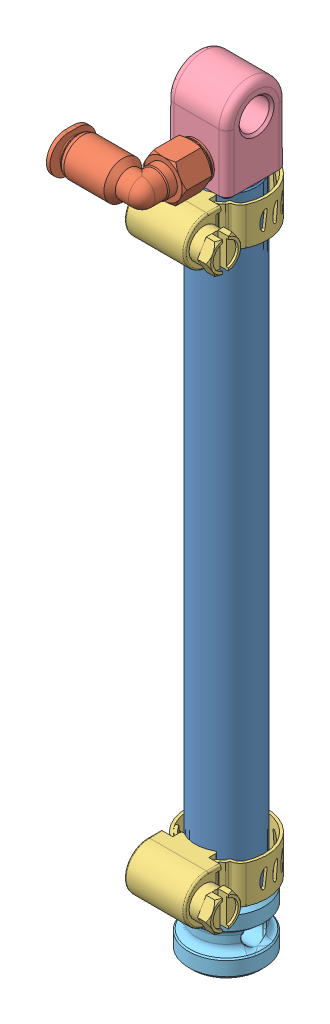
SolidWorks assembly AARL_QR_PN_PA_FL_SH_EX-Extensor, configuration Default. Lengths in mm.
Overall size (26.6 161.92 31.28).
6 component instances, 5 part files, 15 mates.
Components (placement in the parent):
- AARL_QR_PN_PA_FL_SH_EX_001-1: AARL_QR_PN_PA_FL_SH_EX_001 [Resting] at origin size (12.7 130.18 12.7)
- AARL_Puppy_18_02_57_010-QSML-M3-4-1: AARL_Puppy_18_02_57_010-QSML-M3-4 [Default] at (0 69.85 17.85) x (-1 0 0) z (0 0 -1) size (20.32 8 18.9)
- AARL_Puppy_18_02_57_011-5388K140_Hose-Clamp-1: AARL_Puppy_18_02_57_011-5388K140_Hose-Clamp [5388K14] at (0 -60.1345 0) x (1 0 0) z (0 -1 0) size (19.43 23.71 9.91)
- AARL_Puppy_18_02_57_011-5388K140_Hose-Clamp-2: AARL_Puppy_18_02_57_011-5388K140_Hose-Clamp [5388K14] at (0 60.1345 0) x (1 0 0) z (0 -1 0) size (19.43 23.71 9.91)
- AARL_QR_PN_EP_001-1: AARL_QR_PN_EP_001 [Default] at (0 77.7875 0) x (0 0 1) z (-1 0 0) size (12.7 31.75 12.7)
- AARL_QR_PN_EP_002-1: AARL_QR_PN_EP_002 [Default] at (0 -65.0875 0) x (-1 0 0) z (0 0 1) size (15.88 25.4 15.88)
Mates (geometry in assembly coordinates):
- Concentric1: concentric aligned: cylinder of AARL_QR_PN_PA_FL_SH_EX_001-1 through (0 11.6086 0) axis (0 1 0) radius 4.7625; cylinder of AARL_QR_PN_EP_001-1 through (0 87.3315 0) axis (0 1 0) radius 4.3656
- Parallel1: parallel aligned: plane of AARL_QR_PN_EP_001-1 through (-6.35 65.0875 6.35) normal (0 0 1)
- Coincident2: coincident anti-aligned: plane of AARL_QR_PN_PA_FL_SH_EX_001-1 through (4.7625 65.0875 0) normal (0 1 0); plane of AARL_QR_PN_EP_001-1 through (-6.35 65.0875 -6.35) normal (0 -1 0)
- Concentric2: concentric aligned: cylinder of AARL_Puppy_18_02_57_010-QSML-M3-4-1 through (0 69.85 6.35) axis (0 0 1) radius 1.5; cylinder of AARL_QR_PN_EP_001-1 through (0 69.85 6.35) axis (0 0 1) radius 2.0193
- Coincident3: coincident anti-aligned: plane of AARL_Puppy_18_02_57_010-QSML-M3-4-1 through (0 69.85 6.35) normal (0 0 -1); plane of AARL_QR_PN_EP_001-1 through (-6.35 65.0875 6.35) normal (0 0 1)
- Parallel2: parallel aligned: plane of AARL_Puppy_18_02_57_010-QSML-M3-4-1 through (2.3094 65.85 13.4056) normal (0 -1 0); plane of AARL_QR_PN_EP_001-1 through (-6.35 65.0875 -6.35) normal (0 -1 0)
- Concentric3: concentric anti-aligned: cylinder of AARL_QR_PN_PA_FL_SH_EX_001-1 through (0 11.6086 0) axis (0 1 0) radius 4.7625; cylinder of AARL_QR_PN_EP_002-1 through (0 -72.8252 0) axis (0 -1 0) radius 4.3656
- Coincident5: coincident anti-aligned: plane of AARL_QR_PN_PA_FL_SH_EX_001-1 through (6.35 -65.0875 0) normal (0 -1 0); plane of AARL_QR_PN_EP_002-1 through (-4.3656 -65.0875 0) normal (0 1 0)
- Parallel3: parallel anti-aligned: cylinder of AARL_QR_PN_EP_001-1 through (-6.35 77.7875 0) axis (1 0 0) radius 3.175; cylinder of AARL_QR_PN_EP_002-1 through (7.9375 -71.4375 0) axis (-1 0 0) radius 2.3813
- Concentric5: concentric aligned: cylinder of AARL_QR_PN_PA_FL_SH_EX_001-1 through (0 11.6086 0) axis (0 1 0) radius 6.35; cylinder of AARL_Puppy_18_02_57_011-5388K140_Hose-Clamp-2 through (0 56.1658 0) axis (0 1 0) radius 7.9375
- Coincident6: coincident aligned: plane of AARL_Puppy_18_02_57_011-5388K140_Hose-Clamp-2 through (6.35 60.1345 10.2337) normal (1 0 0); plane of AARL_QR_PN_EP_001-1 through (6.35 77.7875 0) normal (1 0 0)
- Coincident7: coincident anti-aligned: plane of AARL_Puppy_18_02_57_011-5388K140_Hose-Clamp-2 through (0 65.0875 0) normal (0 1 0); plane of AARL_QR_PN_EP_001-1 through (-6.35 65.0875 -6.35) normal (0 -1 0)
- Concentric6: concentric aligned: cylinder of AARL_QR_PN_PA_FL_SH_EX_001-1 through (0 11.6086 0) axis (0 1 0) radius 6.35; cylinder of AARL_Puppy_18_02_57_011-5388K140_Hose-Clamp-1 through (0 -64.1033 0) axis (0 1 0) radius 7.9375
- Coincident8: coincident aligned: plane of AARL_Puppy_18_02_57_011-5388K140_Hose-Clamp-1 through (6.35 -60.1345 10.2337) normal (1 0 0); plane of AARL_Puppy_18_02_57_011-5388K140_Hose-Clamp-2 through (6.35 60.1345 10.2337) normal (1 0 0)
- Coincident9: coincident anti-aligned: plane of AARL_Puppy_18_02_57_011-5388K140_Hose-Clamp-1 through (0 -65.0875 0) normal (0 -1 0); plane of AARL_QR_PN_EP_002-1 through (-4.3656 -65.0875 0) normal (0 1 0)
